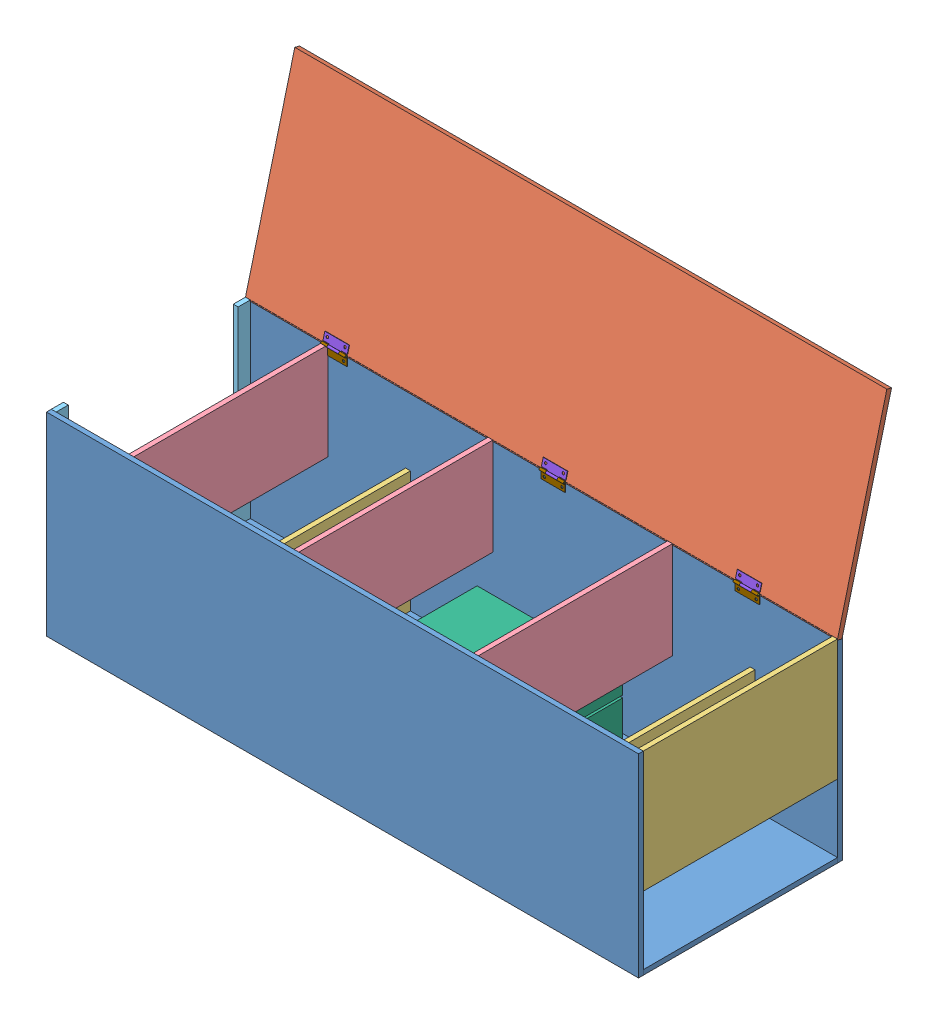
SolidWorks assembly Simplistic, configuration Default. Lengths in mm.
Overall size (1220.05 795 521.38).
24 component instances, 9 part files, 40 mates.
Components (placement in the parent):
- Boards-1: Boards [Default] at (-202.3663 615.2387 1159.9224) size (1220 10 400)
- Boards-2: Boards [Default] at (-202.3663 645.6537 1190.3374) x (1 0 0) z (0 -1 0) size (1220 10 400)
- Boards-3: Boards [Default] at (-202.3663 645.6537 780.3374) x (1 0 0) z (0 -1 0) size (1220 10 400)
- Top Board-4: Top Board [Default] at (944.4815 1013.1632 790.79) x (-1 0 0) z (0 -0.96847 0.249129) size (1220 10 410)
- Panel-1: Panel [Default] at (944.4315 765.2387 790.3374) x (0 0 1) z (-1 0 0) size (400 250 10)
- Panel-2: Panel [Default] at (774.4315 625.2387 790.3374) x (0 0 1) z (-1 0 0) size (400 250 10)
- Short Panel-3: Short Panel [Default] at (604.4315 815.2387 790.3374) x (0 0 1) z (-1 0 0) size (400 200 10)
- Short Panel-4: Short Panel [Default] at (234.4315 815.2387 790.3374) x (0 0 1) z (-1 0 0) size (400 200 10)
- Panel-5: Panel [Default] at (54.4315 875.2387 790.3374) x (0 0 1) z (1 0 0) size (400 250 10)
- Exhaust End-1: Exhaust End [Default] at (-275.5685 625.2387 1190.3374) x (0 0 -1) z (1 0 0) size (400 390 10)
- Antminer S17-1: Antminer S17 [Default] at (528.2792 795.2387 846.7777) x (-1 0 0) z (0 1 0) size (330 298 170)
- Hinge-1: Hinge [Default] at (-97.226 996.7387 790.3374) x (1 0 0) z (0 0 -1) size (52 37.04 10.07)
  - Pin-1: Pin [Default] at (-19.3424 -18.5 -2.5) x (1 0 0) z (0 0.540208 0.841532) size (52 4.2 4.2)
  - Wing 1-1: Wing 1 [Default] at (6.6576 -25.8741 0.9457) x (1 0 0) z (0 0.96847 -0.249129) size (50 5 21)
  - Wing 2-1: Wing 2 [Default] at (6.6576 -10.5 -1) x (-1 0 0) z (0 -1 0) size (50 5 21)
- Hinge-2: Hinge [Default] at (352.774 996.7387 790.3374) x (1 0 0) z (0 0 -1) size (52 37.04 10.07)
  - Pin-1: Pin [Default] at (-19.3424 -18.5 -2.5) x (1 0 0) z (0 0.540208 0.841532) size (52 4.2 4.2)
  - Wing 1-1: Wing 1 [Default] at (6.6576 -25.8741 0.9457) x (1 0 0) z (0 0.96847 -0.249129) size (50 5 21)
  - Wing 2-1: Wing 2 [Default] at (6.6576 -10.5 -1) x (-1 0 0) z (0 -1 0) size (50 5 21)
- Hinge-3: Hinge [Default] at (752.774 996.7387 790.3374) x (1 0 0) z (0 0 -1) size (52 37.04 10.07)
  - Pin-1: Pin [Default] at (-19.3424 -18.5 -2.5) x (1 0 0) z (0 0.540208 0.841532) size (52 4.2 4.2)
  - Wing 1-1: Wing 1 [Default] at (6.6576 -25.8741 0.9457) x (1 0 0) z (0 0.96847 -0.249129) size (50 5 21)
  - Wing 2-1: Wing 2 [Default] at (6.6576 -10.5 -1) x (-1 0 0) z (0 -1 0) size (50 5 21)
- Short Panel-5: Short Panel [Default] at (-115.5685 815.2387 1190.3374) x (0 0 -1) z (1 0 0) size (400 200 10)
Mates (geometry in assembly coordinates):
- Coincident3: coincident aligned: line of Boards-1 through (-275.5685 615.2387 1190.3374) axis (1 0 0); line of Boards-2 through (-275.5685 615.2387 1190.3374) axis (1 0 0)
- Coincident4: coincident aligned: line of Boards-1 through (944.4315 625.2387 1190.3374) axis (0 -1 0); line of Boards-2 through (944.4315 1015.2387 1190.3374) axis (0 -1 0)
- Coincident6: coincident aligned: line of Boards-1 through (-275.5685 615.2387 790.3374) axis (1 0 0); line of Boards-3 through (-275.5685 615.2387 790.3374) axis (1 0 0)
- Coincident8: coincident aligned: line of Boards-1 through (944.4315 625.2387 790.3374) axis (0 -1 0); line of Boards-3 through (944.4315 1015.2387 790.3374) axis (0 -1 0)
- Coincident14: coincident anti-aligned: line of Boards-2 through (944.4315 1015.2387 1190.3374) axis (0 -1 0); line of Panel-1 through (944.4315 765.2387 1190.3374) axis (0 1 0)
- Coincident15: coincident aligned: line of Boards-3 through (944.4315 1015.2387 790.3374) axis (0 -1 0); line of Panel-1 through (944.4315 1015.2387 790.3374) axis (0 -1 0)
- Coincident17: coincident aligned: line of Boards-3 through (-275.5685 1015.2387 790.3374) axis (1 0 0); line of Panel-1 through (934.4315 1015.2387 790.3374) axis (1 0 0)
- Coincident18: coincident anti-aligned: line of Boards-1 through (-275.5685 625.2387 790.3374) axis (0 0 1); line of Exhaust End-1 through (-275.5685 625.2387 1190.3374) axis (0 0 -1)
- Coincident19: coincident aligned: line of Boards-2 through (-275.5685 1015.2387 1190.3374) axis (0 -1 0); line of Exhaust End-1 through (-275.5685 1015.2387 1190.3374) axis (0 -1 0)
- Coincident21: coincident anti-aligned: plane of Boards-3 through (-202.3663 645.6537 790.3374) normal (0 0 1); plane of Panel-2 through (764.4315 625.2387 790.3374) normal (0 0 -1)
- Coincident22: coincident anti-aligned: plane of Boards-1 through (-202.3663 625.2387 1159.9224) normal (0 1 0); plane of Panel-2 through (764.4315 625.2387 790.3374) normal (0 -1 0)
- Coincident23: coincident anti-aligned: plane of Boards-2 through (-202.3663 645.6537 1190.3374) normal (0 0 -1); plane of Short Panel-3 through (594.4315 815.2387 1190.3374) normal (0 0 1)
- Coincident24: coincident aligned: line of Boards-2 through (-275.5685 1015.2387 1190.3374) axis (1 0 0); line of Short Panel-3 through (594.4315 1015.2387 1190.3374) axis (1 0 0)
- Coincident25: coincident anti-aligned: plane of Boards-2 through (-202.3663 645.6537 1190.3374) normal (0 0 -1); plane of Short Panel-4 through (224.4315 815.2387 1190.3374) normal (0 0 1)
- Coincident26: coincident aligned: line of Boards-2 through (-275.5685 1015.2387 1190.3374) axis (1 0 0); line of Short Panel-4 through (224.4315 1015.2387 1190.3374) axis (1 0 0)
- Coincident27: coincident anti-aligned: plane of Boards-1 through (-202.3663 625.2387 1159.9224) normal (0 1 0); plane of Panel-5 through (54.4315 625.2387 790.3374) normal (0 -1 0)
- Coincident28: coincident anti-aligned: plane of Boards-3 through (-202.3663 645.6537 790.3374) normal (0 0 1); plane of Panel-5 through (54.4315 875.2387 790.3374) normal (0 0 -1)
- Distance1: distance = 160 mm anti-aligned: plane of Panel-1 through (934.4315 765.2387 790.3374) normal (-1 0 0); plane of Panel-2 through (774.4315 625.2387 790.3374) normal (1 0 0)
- Distance2: distance = 160 mm anti-aligned: plane of Panel-2 through (764.4315 625.2387 790.3374) normal (-1 0 0); plane of Panel-3 through (604.4315 815.2387 790.3374) normal (1 0 0)
- Distance3: distance = 360 mm anti-aligned: plane of Panel-3 through (594.4315 815.2387 790.3374) normal (-1 0 0); plane of Panel-4 through (234.4315 815.2387 790.3374) normal (1 0 0)
- Distance4: distance = 160 mm anti-aligned: plane of Panel-4 through (224.4315 815.2387 790.3374) normal (-1 0 0); plane of Panel-5 through (64.4315 875.2387 790.3374) normal (1 0 0)
- Coincident29: coincident anti-aligned: plane of Boards-1 through (-202.3663 625.2387 1159.9224) normal (0 1 0); plane of Antminer S17-1 through (528.2792 625.2387 1144.7777) normal (0 -1 0)
- Parallel1: parallel anti-aligned: plane of Boards-2 through (-202.3663 645.6537 1190.3374) normal (0 0 -1); plane of Antminer S17-1 through (528.2792 795.2387 1144.7777) normal (0 0 1)
- Coincident31: coincident anti-aligned: plane of Boards-3 through (-202.3663 645.6537 790.3374) normal (0 0 1); plane of Hinge-1/Wing 2-1 through (-115.5685 1017.7387 790.3374) normal (0 0 -1)
- Parallel3: parallel anti-aligned: plane of Panel-5 through (54.4315 875.2387 790.3374) normal (0 1 0); plane of Hinge-1/Wing 2-1 through (-65.5685 996.7387 790.3374) normal (0 -1 0)
- Coincident42: coincident aligned: line of Boards-3 through (-275.5685 1015.2387 790.3374) axis (1 0 0); line of Hinge-1/Wing 2-1 through (-78.5685 1015.2387 790.3374) axis (1 0 0)
- Distance5: distance = 150 mm anti-aligned: plane of Hinge-1/Wing 1-1 through (-115.5685 1032.5326 785.8074) normal (-1 0 0); plane of Exhaust End-1 through (-265.5685 625.2387 1190.3374) normal (1 0 0)
- Coincident44: coincident anti-aligned: plane of Boards-3 through (-202.3663 645.6537 790.3374) normal (0 0 1); plane of Hinge-2/Wing 2-1 through (334.4315 1017.7387 790.3374) normal (0 0 -1)
- Parallel9: parallel anti-aligned: plane of Boards-1 through (-202.3663 625.2387 1159.9224) normal (0 1 0); plane of Hinge-2/Wing 2-1 through (384.4315 996.7387 790.3374) normal (0 -1 0)
- Coincident46: coincident aligned: line of Boards-3 through (-275.5685 1015.2387 790.3374) axis (1 0 0); line of Hinge-2/Wing 2-1 through (334.4315 1015.2387 790.3374) axis (1 0 0)
- Coincident47: coincident anti-aligned: plane of Boards-3 through (-202.3663 645.6537 790.3374) normal (0 0 1); plane of Hinge-3/Wing 2-1 through (734.4315 1017.7387 790.3374) normal (0 0 -1)
- Parallel10: parallel anti-aligned: plane of Boards-1 through (-202.3663 625.2387 1159.9224) normal (0 1 0); plane of Hinge-3/Wing 2-1 through (784.4315 996.7387 790.3374) normal (0 -1 0)
- Coincident49: coincident aligned: line of Boards-3 through (-275.5685 1015.2387 790.3374) axis (1 0 0); line of Hinge-3/Wing 2-1 through (771.4315 1015.2387 790.3374) axis (1 0 0)
- Distance6: distance = 150 mm anti-aligned: plane of Hinge-3/Wing 2-1 through (784.4315 996.7387 790.3374) normal (1 0 0); plane of Panel-1 through (934.4315 765.2387 790.3374) normal (-1 0 0)
- Distance7: distance = 550 mm anti-aligned: plane of Panel-1 through (934.4315 765.2387 790.3374) normal (-1 0 0); plane of Hinge-2/Wing 2-1 through (384.4315 996.7387 790.3374) normal (1 0 0)
- Coincident63: coincident anti-aligned: circle of Top Board-4; circle of Hinge-3/Wing 1-1
- Coincident64: coincident anti-aligned: circle of Top Board-4; circle of Hinge-3/Wing 1-1
- Coincident65: coincident anti-aligned: plane of Boards-3 through (-202.3663 645.6537 790.3374) normal (0 0 1); plane of Short Panel-5 through (-125.5685 815.2387 790.3374) normal (0 0 -1)
- Coincident66: coincident anti-aligned: line of Boards-3 through (-275.5685 1015.2387 790.3374) axis (1 0 0); line of Short Panel-5 through (-125.5685 1015.2387 790.3374) axis (-1 0 0)
- Distance8: distance = 150 mm anti-aligned: plane of Exhaust End-1 through (-265.5685 625.2387 1190.3374) normal (1 0 0); plane of Short Panel-5 through (-115.5685 815.2387 1190.3374) normal (-1 0 0)
